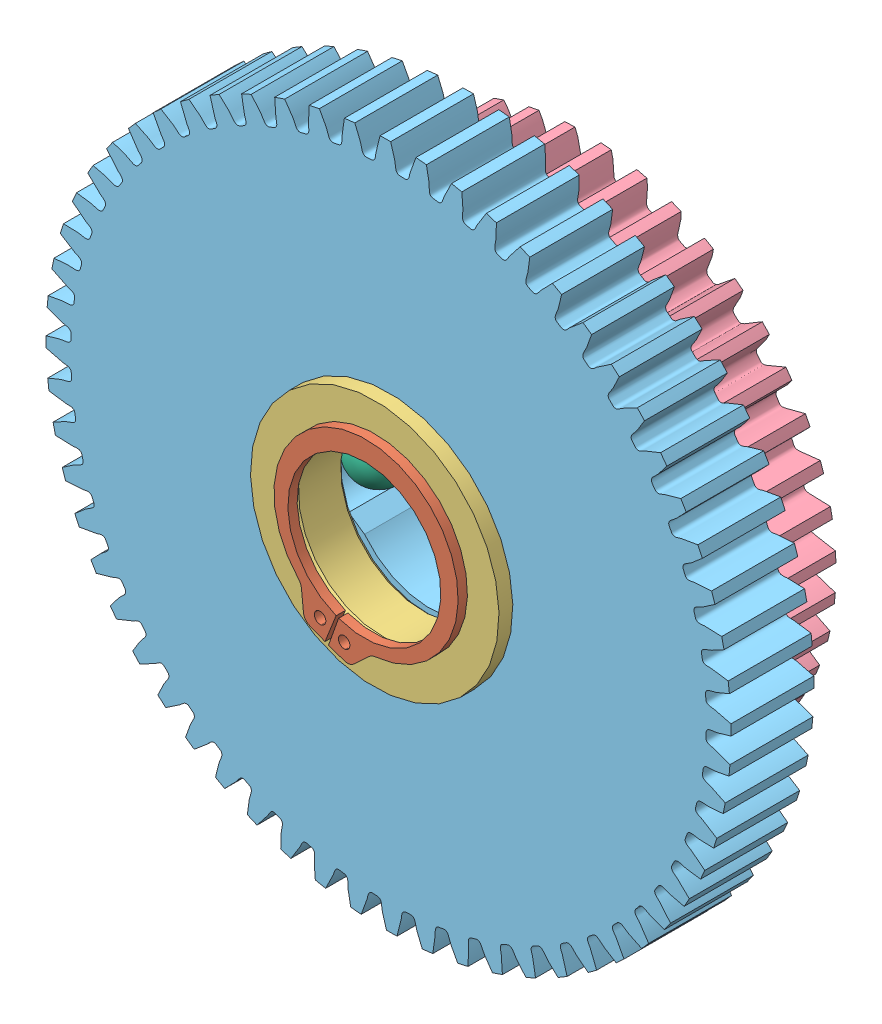
SolidWorks assembly Short Shaft ear box, configuration Default. Lengths in mm.
Overall size (112.15 112.15 28.2).
15 component instances, 6 part files, 0 mates.
Components (placement in the parent):
- 217-2428-008 Rev1-1: 217-2428-008 Rev1 [Default] at (0 0 10.2679) size (31.75 31.75 1.59)
- 217-2428-028 Rev1_97633A250-1: 217-2428-028 Rev1_97633A250 [Default] at (0 0 37.1221) x (0 0 1) z (0.9357 -0.352797 0) size (1.07 23.39 21.18)
- 217-2709-101 Rev1-1: 217-2709-101 Rev1 [Default] at (0 0 20.7137) x (0.683646 -0.729814 0) z (0 0 -1) size (62.31 62.31 12.7)
  - 217-2428-022 Rev1-1: 217-2428-022 Rev1 [Default] at origin size (28.57 28.57 6.1)
  - 217-2709-001_44t Steel-1: 217-2709-001_44t Steel [Default] at (0 0 3.302) x (0.062728 -0.998031 0) z (0 0 1) size (58.74 58.74 11.11)
- 217-2713-101 Rev1-1: 217-2713-101 Rev1 [Default] at (0 0 33.4137) x (0.795075 0.606511 0) z (0 0 -1) size (81.88 81.88 12.7)
  - 217-2713-001_60t Steel-1: 217-2713-001_60t Steel [Default] at (0 0 3.302) x (0.999266 -0.038302 0) z (0 0 1) size (78.91 78.91 11.11)
  - 217-2428-022 Rev1-1: 217-2428-022 Rev1 [Default] at origin size (28.57 28.57 6.1)
- 217-2791 Rev1-1: 217-2791 Rev1 [Default] x (-1 0 0) z (0 0 1) (suppressed, hidden)
- 217-2428-007 Rev1-1: 217-2428-007 Rev1 [Default] at (-6.3246 0 14.2494) x (-0.433689 -0.073373 -0.89807) z (-0.363902 -0.897521 0.249061) size (6.35 6.35 6.35)
- 217-2428-007 Rev1-2: 217-2428-007 Rev1 [Default] at (-9.017 0 26.9494) x (-0.162331 -0.978398 0.128005) z (0.857281 -0.204076 -0.472676) size (6.35 6.35 6.35)
- 217-2428-007 Rev1-3: 217-2428-007 Rev1 [Default] at (3.1623 -5.4773 14.2494) x (0.280387 -0.338899 -0.89807) z (0.959227 0.133612 0.249061) size (6.35 6.35 6.35)
- 217-2428-007 Rev1-4: 217-2428-007 Rev1 [Default] at (3.1623 5.4773 14.2494) x (0.153301 0.412272 -0.89807) z (-0.595325 0.763909 0.249061) size (6.35 6.35 6.35)
- 217-2428-007 Rev1-5: 217-2428-007 Rev1 [Default] at (4.5085 -7.809 26.9494) x (0.928483 0.348617 0.128005) z (-0.251905 0.844465 -0.472676) size (6.35 6.35 6.35)
- 217-2428-007 Rev1-6: 217-2428-007 Rev1 [Default] at (4.5085 7.809 26.9494) x (-0.766153 0.629782 0.128005) z (-0.605376 -0.640389 -0.472676) size (6.35 6.35 6.35)
